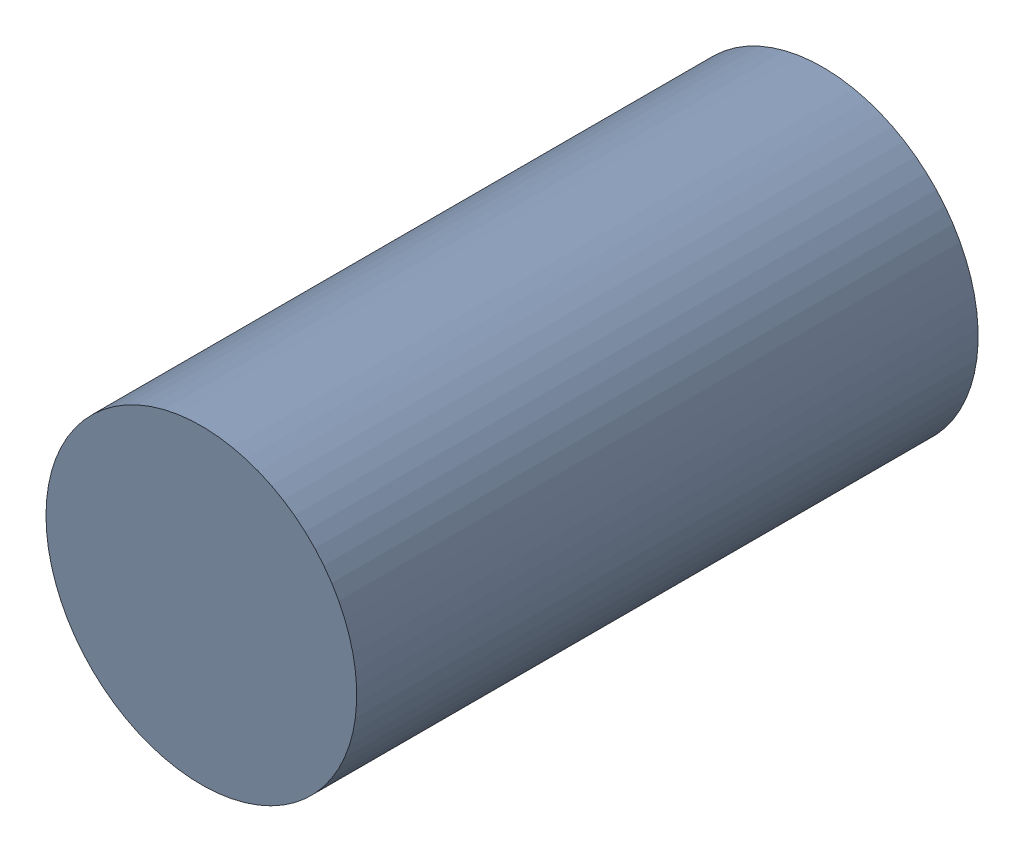
SolidWorks assembly MH10, configuration Default. Lengths in mm.
Overall size (1 1 2).
2 component instances, 1 part files, 0 mates.
Components (placement in the parent):
- 11929539264-1: 11929539264 [Default] at (59.1743 54.2886 -1.5) x (-1 0 0) z (0 0 1) size (1 1 2)
  - Cylinder-1: Cylinder [Default] at origin size (1 1 2)
